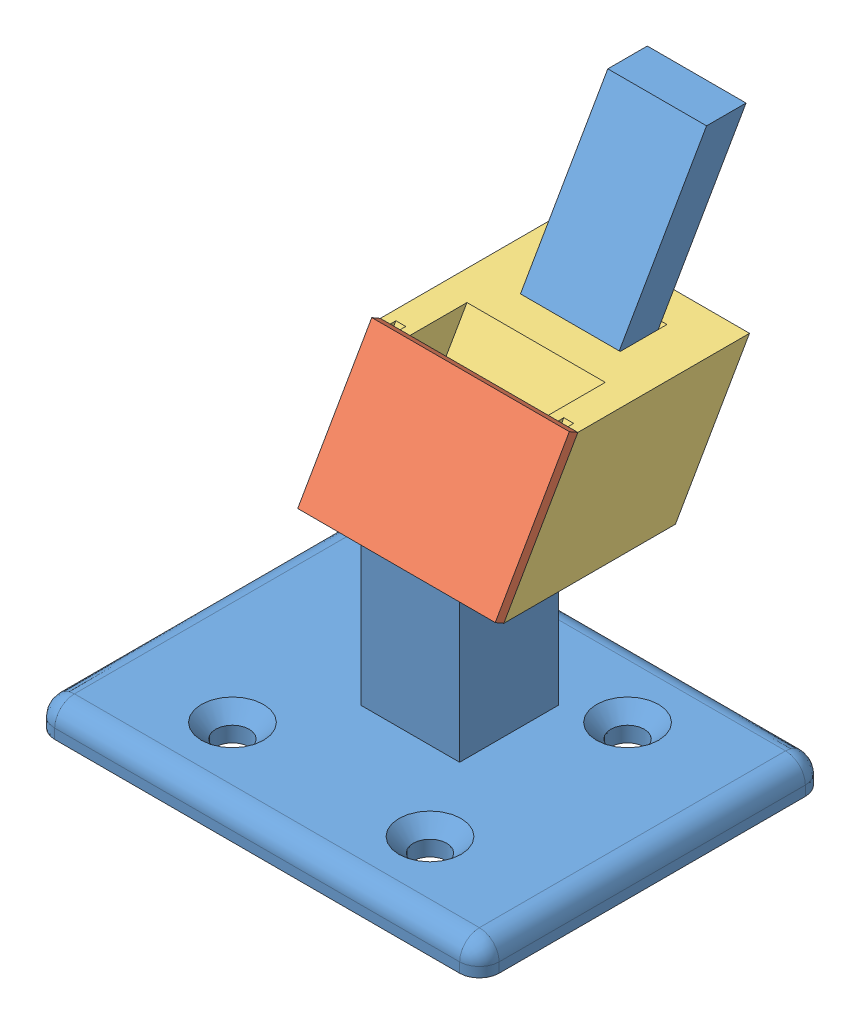
SolidWorks assembly Assembly, configuration Default. Lengths in mm.
Overall size (45 46.3 44.5).
4 component instances, 4 part files, 8 mates.
Components (placement in the parent):
- base-1: base [Default] at (15.0271 12.8544 42.6967) size (45 46.3 44.5)
- sample-1: sample [Default] at (15.0771 37.3461 41.526) x (1 0 0) z (0 0.5 0.866025) size (20 15 1)
- top2-1: top2 [Default] at (15.0771 33.6637 32.0473) x (0 -0.5 -0.866025) z (1 0 0) (suppressed, hidden)
- top-1: top [Default] at (15.0771 25.8259 36.5725) x (0 -0.5 -0.866025) z (1 0 0) size (15.05 23.69 20)
Mates (geometry in assembly coordinates):
- Coincident11: coincident anti-aligned: plane of base-1 through (10.0271 59.1557 19.6967) normal (0 0.5 0.866025); plane of top2-1 through (15.0771 34.6887 33.8227) normal (0 -0.5 -0.866025)
- Coincident12: coincident anti-aligned: plane of base-1 through (10.0271 59.1557 19.6967) normal (-1 0 0); plane of top2-1 through (10.0271 34.6887 33.8227) normal (1 0 0)
- Coincident13: coincident aligned: line of sample-1 through (25.0771 38.6887 40.7509) axis (0 0.866025 -0.5); line of top2-1 through (25.0771 38.6887 40.7509) axis (0 0.866025 -0.5)
- Coincident14: coincident aligned: line of sample-1 through (5.0771 38.6887 40.7509) axis (1 0 0); line of top2-1 through (5.0771 38.6887 40.7509) axis (1 0 0)
- Coincident17: coincident anti-aligned: plane of base-1 through (10.0271 59.1557 19.6967) normal (0 0.5 0.866025); plane of top-1 through (15.0771 26.8509 38.3478) normal (0 -0.5 -0.866025)
- Coincident18: coincident anti-aligned: plane of base-1 through (10.0271 59.1557 19.6967) normal (-1 0 0); plane of top-1 through (10.0271 26.8509 38.3478) normal (1 0 0)
- Coincident19: coincident anti-aligned: plane of sample-1 through (15.0771 37.3461 41.526) normal (0 -0.5 -0.866025); plane of top-1 through (15.0771 30.8509 45.276) normal (0 0.5 0.866025)
- Coincident20: coincident aligned: line of sample-1 through (5.0771 30.8509 45.276) axis (1 0 0); line of top-1 through (5.0771 30.8509 45.276) axis (1 0 0)
